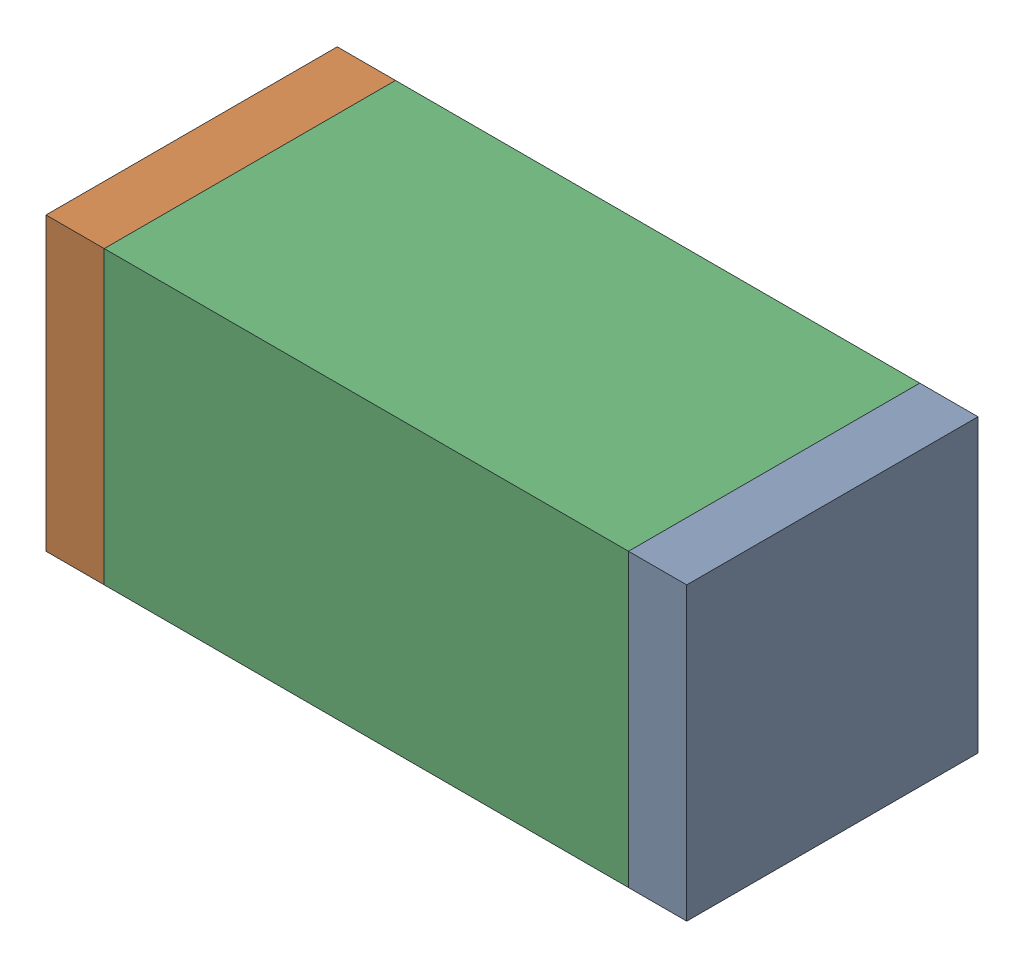
SolidWorks assembly C12, configuration Default. Lengths in mm.
Overall size (1.1 0.5 0.5).
6 component instances, 2 part files, 0 mates.
Components (placement in the parent):
- 810156080-1: 810156080 [Default] at (107.35 10.55 0) size (0.1 0.5 0.5)
  - Extruded_5-1: Extruded_5 [Default] at origin size (0.1 0.5 0.5)
- 810156080-2: 810156080 [Default] at (106.35 10.55 0) size (0.1 0.5 0.5)
  - Extruded_5-1: Extruded_5 [Default] at origin size (0.1 0.5 0.5)
- 836749680-1: 836749680 [Default] at (106.85 10.55 0) size (0.9 0.5 0.5)
  - Extruded_4-1: Extruded_4 [Default] at origin size (0.9 0.5 0.5)
